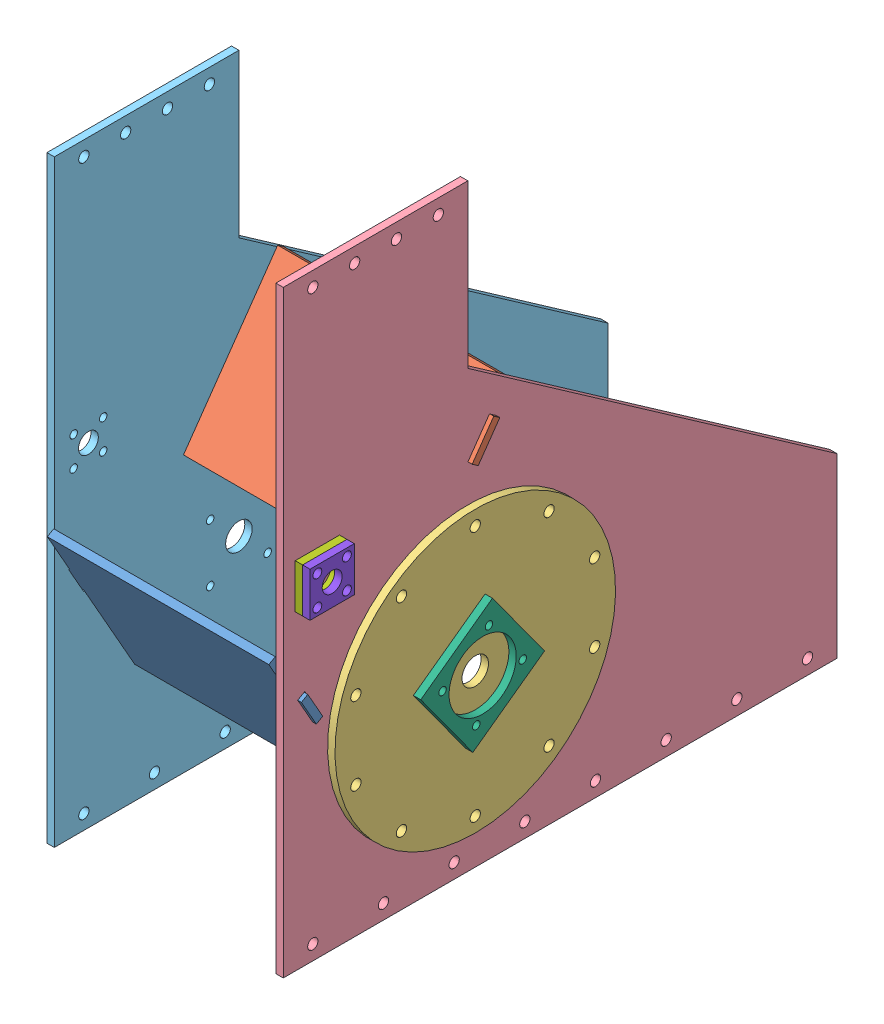
SolidWorks assembly Türbin Montajlı, configuration Varsayılan. Lengths in mm.
Overall size (345 835.39 765.39).
8 component instances, 8 part files, 22 mates.
Components (placement in the parent):
- Su Sabit Yönlendirici_ALT-1: Su Sabit Yönlendirici_ALT [Varsayılan] at (-1109.3991 -8.4071 641.6879) x (1 0 0) z (0 -0.493184 0.869925) size (330 240 10)
- Su Sabit Yönlendirici_ÜST-1: Su Sabit Yönlendirici_ÜST [Varsayılan] at (-1109.3991 180.1569 453.1946) x (1 0 0) z (0 0.573462 0.819232) size (330 222.47 10)
- Türbin Dış kapak-1: Türbin Dış kapak [Varsayılan] at (-949.3991 -36.3049 450) x (0 0.587785 -0.809017) z (1 0 0) size (380 380 10)
- Türbin Dış Yan Panel_SAG-1: Türbin Dış Yan Panel_SAG [Varsayılan] at (-959.3991 -36.3049 450) size (10 810 750)
- Türbin Dış Yan Panel_SOL-1: Türbin Dış Yan Panel_SOL [Varsayılan] at (-1269.3991 -38.1757 450.0889) size (10 810 750)
- Turbin Tutucu_1(Üzerine Yataklı Rulman Monte edilecek)-1: Turbin Tutucu_1(Üzerine Yataklı Rulman Monte edilecek) [Varsayılan] at (-929.3991 -36.3049 450) x (0 -0.587785 0.809017) z (-1 0 0) size (120 120 10)
- Vana Tutucu_1(Keçenin Yeri)-1: Vana Tutucu_1(Keçenin Yeri) [Varsayılan] at (-939.3991 175.0691 653.8121) x (0 0 1) z (-1 0 0) size (60 60 10)
- Vana Tutucu_2(Keçenin üzerine takılacak)-1: Vana Tutucu_2(Keçenin üzerine takılacak) [Varsayılan] at (-929.3991 175.0691 653.8121) x (0 0 1) z (-1 0 0) size (60 60 10)
Mates (geometry in assembly coordinates):
- Çakışık2: coincident anti-aligned: plane of Su Sabit Yönlendirici_ÜST-1 through (-959.3991 245.1098 419.9342) normal (0 0.819232 -0.573462); plane of Türbin Dış Yan Panel_SAG-1 through (-949.3991 245.6832 420.7534) normal (0 -0.819232 0.573462)
- Çakışık3: coincident anti-aligned: plane of Su Sabit Yönlendirici_ÜST-1 through (-1109.3991 180.1569 453.1946) normal (0 -0.573462 -0.819232); plane of Türbin Dış Yan Panel_SAG-1 through (-949.3991 239.3751 411.7419) normal (0 0.573462 0.819232)
- Çakışık4: coincident anti-aligned: plane of Su Sabit Yönlendirici_ÜST-1 through (-959.3991 277.0188 397.5978) normal (1 0 0); plane of Türbin Dış Yan Panel_SAG-1 through (-959.3991 -36.3049 450) normal (-1 0 0)
- Paralel2: parallel aligned: plane of Türbin Dış Yan Panel_SAG-1 through (-949.3991 -236.3049 700) normal (0 0 1); plane of Türbin Dış Yan Panel_SOL-1 through (-1259.3991 -238.1757 700.0889) normal (0 0 1)
- Çakışık5: coincident anti-aligned: plane of Su Sabit Yönlendirici_ALT-1 through (-959.3991 39.7265 680.4713) normal (0 0.869925 0.493184); plane of Türbin Dış Yan Panel_SAG-1 through (-949.3991 45.1515 670.9021) normal (0 -0.869925 -0.493184)
- Çakışık6: coincident anti-aligned: plane of Su Sabit Yönlendirici_ALT-1 through (-1109.3991 -13.3389 650.3871) normal (0 -0.493184 0.869925); plane of Türbin Dış Yan Panel_SAG-1 through (-949.3991 4.0596 660.2508) normal (0 0.493184 -0.869925)
- Çakışık7: coincident anti-aligned: plane of Su Sabit Yönlendirici_ALT-1 through (-959.3991 91.0521 709.5692) normal (1 0 0); plane of Türbin Dış Yan Panel_SAG-1 through (-959.3991 -36.3049 450) normal (-1 0 0)
- Çakışık8: coincident anti-aligned: plane of Su Sabit Yönlendirici_ÜST-1 through (-1109.3991 185.8916 461.3869) normal (0 0.573462 0.819232); plane of Türbin Dış Yan Panel_SOL-1 through (-1259.3991 243.8124 420.8423) normal (0 -0.573462 -0.819232)
- Çakışık9: coincident anti-aligned: plane of Su Sabit Yönlendirici_ÜST-1 through (-1259.3991 94.7643 525.176) normal (-1 0 0); plane of Türbin Dış Yan Panel_SOL-1 through (-1259.3991 -38.1757 450.0889) normal (1 0 0)
- Çakışık10: coincident anti-aligned: plane of Su Sabit Yönlendirici_ALT-1 through (-1109.3991 -8.4071 641.6879) normal (0 0.493184 -0.869925); plane of Türbin Dış Yan Panel_SOL-1 through (-1259.3991 7.6138 650.7705) normal (0 -0.493184 0.869925)
- Eş Merkezli1: concentric anti-aligned: cylinder of Türbin Dış kapak-1 through (-939.3991 133.6951 450) axis (-1 0 0) radius 7; circle of Türbin Dış Yan Panel_SAG-1
- Eş Merkezli2: concentric aligned: circle of Türbin Dış kapak-1; circle of Türbin Dış Yan Panel_SAG-1
- Çakışık11: coincident anti-aligned: plane of Türbin Dış kapak-1 through (-949.3991 -36.3049 450) normal (-1 0 0); plane of Türbin Dış Yan Panel_SAG-1 through (-949.3991 -36.3049 450) normal (1 0 0)
- Eş Merkezli3: concentric anti-aligned: cylinder of Türbin Dış kapak-1 through (-939.3991 -36.3049 450) axis (-1 0 0) radius 18; cylinder of Turbin Tutucu_1(Üzerine Yataklı Rulman Monte edilecek)-1 through (-939.3991 -36.3049 450) axis (1 0 0) radius 45.5
- Eş Merkezli4: concentric aligned: circle of Türbin Dış kapak-1; cylinder of Turbin Tutucu_1(Üzerine Yataklı Rulman Monte edilecek)-1 through (-939.3991 18.018 441.3961) axis (1 0 0) radius 5.1
- Çakışık12: coincident anti-aligned: plane of Türbin Dış kapak-1 through (-939.3991 -36.3049 450) normal (1 0 0); plane of Turbin Tutucu_1(Üzerine Yataklı Rulman Monte edilecek)-1 through (-939.3991 -36.3049 450) normal (-1 0 0)
- Eş Merkezli5: concentric anti-aligned: cylinder of Türbin Dış Yan Panel_SAG-1 through (-949.3991 175.0691 653.8121) axis (-1 0 0) radius 13.5; cylinder of Vana Tutucu_2(Keçenin üzerine takılacak)-1 through (-939.3991 175.0691 653.8121) axis (1 0 0) radius 13.5
- Eş Merkezli6: concentric anti-aligned: circle of Türbin Dış Yan Panel_SAG-1; circle of Vana Tutucu_2(Keçenin üzerine takılacak)-1
- Eş Merkezli7: concentric anti-aligned: cylinder of Türbin Dış Yan Panel_SAG-1 through (-949.3991 175.0691 653.8121) axis (-1 0 0) radius 13.5; cylinder of Vana Tutucu_1(Keçenin Yeri)-1 through (-949.3991 175.0691 653.8121) axis (1 0 0) radius 18.5
- Eş Merkezli8: concentric anti-aligned: cylinder of Türbin Dış Yan Panel_SAG-1 through (-949.3991 195.0691 633.8121) axis (-1 0 0) radius 5.1; cylinder of Vana Tutucu_1(Keçenin Yeri)-1 through (-949.3991 195.0691 633.8121) axis (1 0 0) radius 6
- Çakışık14: coincident anti-aligned: plane of Türbin Dış Yan Panel_SAG-1 through (-949.3991 -36.3049 450) normal (1 0 0); plane of Vana Tutucu_1(Keçenin Yeri)-1 through (-949.3991 175.0691 653.8121) normal (-1 0 0)
- Çakışık15: coincident anti-aligned: plane of Vana Tutucu_1(Keçenin Yeri)-1 through (-939.3991 175.0691 653.8121) normal (1 0 0); plane of Vana Tutucu_2(Keçenin üzerine takılacak)-1 through (-939.3991 175.0691 653.8121) normal (-1 0 0)
